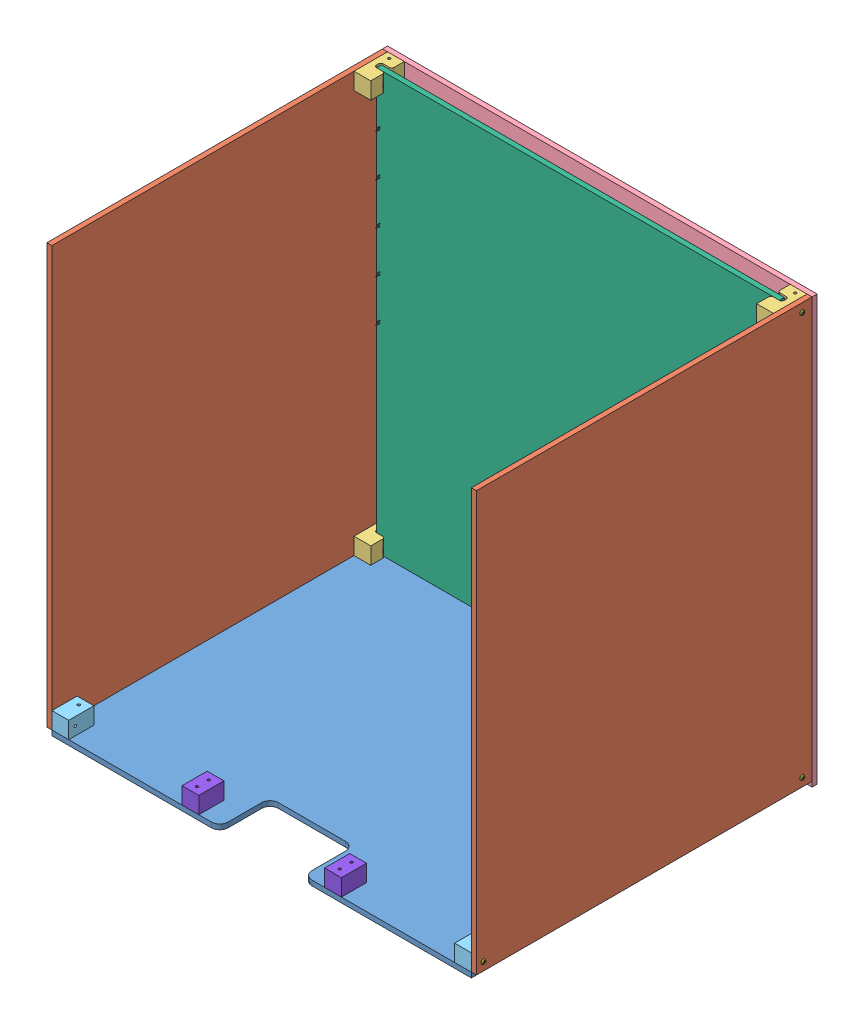
SolidWorks assembly robot_dock, configuration Default. Lengths in mm.
Overall size (515 507.5 407.6).
37 component instances, 9 part files, 84 mates.
Components (placement in the parent):
- back_board-1: back_board [Default] at (-3.0743 -458.0455 33.4938) size (500 6 400)
- side_board-3: side_board [Default] at (496.9257 47.9545 33.4938) x (0 -1 0) z (0 0 1) size (500 6 400)
- side_board-4: side_board [Default] at (-9.0743 47.9545 33.4938) x (0 -1 0) z (0 0 1) size (500 6 400)
- connector-1: connector [Default] at (-3.0743 27.9545 35.3943) size (20 20 40)
- connector-2: connector [Default] at (496.9257 -432.0455 35.3943) x (-1 0 0) z (0 0 1) size (20 20 40)
- connector-4: connector [Default] at (496.9257 47.9545 35.3943) x (-1 0 0) z (0 0 1) size (20 20 40)
- connector-6: connector [Default] at (-3.0743 -452.0455 35.3943) size (20 20 40)
- top_board-1: top_board [Default] at (-3.0743 47.9545 27.4938) x (1 0 0) z (0 -1 0) size (512 6 506)
- back_connector-1: back_connector [Default] at (-3.0743 -452.0455 433.4938) x (1 0 0) z (0 1 0) size (20 30 20)
- back_connector-2: back_connector [Default] at (476.9257 -452.0455 433.4938) x (1 0 0) z (0 1 0) size (20 30 20)
- middle_board-2: middle_board [Default] at (486.9257 -452.0455 56.4938) x (0 1 0) z (-1 0 0) size (500.05 6.1 480)
- Screw_Machine_M3x20-1: Screw_Machine_M3x20 [Default] at (488.9257 -458.0455 39.4938) x (-0.837169 0 -0.546944) z (-0.546944 0 0.837169) size (5.5 21.5 5.5)
- Screw_Machine_M3x20-2: Screw_Machine_M3x20 [Default] at (480.9257 37.9545 27.4938) x (1 0 0) z (0 1 0) size (5.5 21.5 5.5)
- Screw_Machine_M3x20-6: Screw_Machine_M3x20 [Default] at (4.9257 -458.0455 39.4938) x (-1 0 0) z (0 0 1) size (5.5 21.5 5.5)
- Screw_Machine_M3x20-8: Screw_Machine_M3x20 [Default] at (502.9257 -442.0455 425.4938) x (0 0.381849 -0.924225) z (0 -0.924225 -0.381849) size (5.5 21.5 5.5)
- Screw_Machine_M3x20-9: Screw_Machine_M3x20 [Default] at (6.9257 -458.0455 411.4938) x (-0.837169 0 -0.546944) z (-0.546944 0 0.837169) size (5.5 21.5 5.5)
- Screw_Machine_M3x20-10: Screw_Machine_M3x20 [Default] at (-9.0743 -442.0455 45.4938) x (0 1 0) z (0 0 1) size (5.5 21.5 5.5)
- Screw_Machine_M3x20-11: Screw_Machine_M3x20 [Default] at (-9.0743 -442.0455 425.4938) x (0 1 0) z (0 0 1) size (5.5 21.5 5.5)
- Screw_Machine_M3x20-12: Screw_Machine_M3x20 [Default] at (-9.0743 37.9545 45.4938) x (0 1 0) z (0 0 1) size (5.5 21.5 5.5)
- Screw_Machine_M3x20-13: Screw_Machine_M3x20 [Default] at (12.9257 -442.0455 27.4938) x (1 0 0) z (0 1 0) size (5.5 21.5 5.5)
- Screw_Machine_M3x20-14: Screw_Machine_M3x20 [Default] at (480.9257 -442.0455 27.4938) x (1 0 0) z (0 1 0) size (5.5 21.5 5.5)
- Screw_Machine_M3x20-16: Screw_Machine_M3x20 [Default] at (486.9257 -458.0455 411.4938) x (-0.837169 0 -0.546944) z (-0.546944 0 0.837169) size (5.5 21.5 5.5)
- Screw_Machine_M3x20-17: Screw_Machine_M3x20 [Default] at (502.9257 -442.0455 45.4938) x (0 0.381849 -0.924225) z (0 -0.924225 -0.381849) size (5.5 21.5 5.5)
- Screw_Machine_M3x20-19: Screw_Machine_M3x20 [Default] at (12.9257 37.9545 27.4938) x (1 0 0) z (0 1 0) size (5.5 21.5 5.5)
- Screw_Machine_M3x20-20: Screw_Machine_M3x20 [Default] at (502.9257 37.9545 45.4938) x (0 0.381849 -0.924225) z (0 -0.924225 -0.381849) size (5.5 21.5 5.5)
- robot_dock_pilot-1: robot_dock_pilot [Default] at (151.9257 -452.0455 433.4938) x (1 0 0) z (0 1 0) size (20 30 20)
- robot_dock_pilot-2: robot_dock_pilot [Default] at (321.9257 -452.0455 433.4938) x (1 0 0) z (0 1 0) size (20 30 20)
- Led Lamp 5 mm 3-1: Led Lamp 5 mm 3 [Default] at (482.9257 -12.0455 34.4938) x (0 0 -1) z (1 0 0) size (35.6 5.45 5.9)
- Led Lamp 5 mm 3-2: Led Lamp 5 mm 3 [Default] at (10.9257 -212.0455 34.4938) x (0 0 -1) z (1 0 0) size (35.6 5.45 5.9)
- Led Lamp 5 mm 3-3: Led Lamp 5 mm 3 [Default] at (10.9257 -62.0455 34.4938) x (0 0 -1) z (1 0 0) size (35.6 5.45 5.9)
- Led Lamp 5 mm 3-4: Led Lamp 5 mm 3 [Default] at (10.9257 -12.0455 34.4938) x (0 0 -1) z (1 0 0) size (35.6 5.45 5.9)
- Led Lamp 5 mm 3-5: Led Lamp 5 mm 3 [Default] at (482.9257 -212.0455 34.4938) x (0 0 -1) z (1 0 0) size (35.6 5.45 5.9)
- Led Lamp 5 mm 3-6: Led Lamp 5 mm 3 [Default] at (482.9257 -162.0455 34.4938) x (0 0 -1) z (1 0 0) size (35.6 5.45 5.9)
- Led Lamp 5 mm 3-7: Led Lamp 5 mm 3 [Default] at (10.9257 -162.0455 34.4938) x (0 0 -1) z (1 0 0) size (35.6 5.45 5.9)
- Led Lamp 5 mm 3-8: Led Lamp 5 mm 3 [Default] at (10.9257 -112.0455 34.4938) x (0 0 -1) z (1 0 0) size (35.6 5.45 5.9)
- Led Lamp 5 mm 3-10: Led Lamp 5 mm 3 [Default] at (482.9257 -112.0455 34.4938) x (0 0 -1) z (1 0 0) size (35.6 5.45 5.9)
- Led Lamp 5 mm 3-11: Led Lamp 5 mm 3 [Default] at (482.9257 -62.0455 34.4938) x (0 0 -1) z (0.182556 -0.983195 0) size (35.6 5.45 5.9)
Mates (geometry in assembly coordinates):
- Coincident2: coincident anti-aligned: plane of side_board-4 through (-3.0743 47.9545 33.4938) normal (1 0 0); plane of connector-1 through (-3.0743 47.9545 33.4938) normal (-1 0 0)
- Coincident3: coincident aligned: line of side_board-4 through (-3.0743 47.9545 33.4938) axis (0 0 1); line of connector-1 through (-3.0743 47.9545 33.4938) axis (0 0 1)
- Coincident4: coincident aligned: line of side_board-4 through (-3.0743 47.9545 33.4938) axis (0 -1 0); line of connector-1 through (-3.0743 47.9545 33.4938) axis (0 -1 0)
- Coincident5: coincident anti-aligned: plane of side_board-4 through (-3.0743 47.9545 33.4938) normal (1 0 0); plane of connector-6 through (-3.0743 -432.0455 33.4938) normal (-1 0 0)
- Coincident6: coincident aligned: line of side_board-4 through (-3.0743 -452.0455 33.4938) axis (0 0 1); line of connector-6 through (-3.0743 -452.0455 33.4938) axis (0 0 1)
- Coincident7: coincident aligned: line of side_board-4 through (-3.0743 47.9545 33.4938) axis (0 -1 0); line of connector-6 through (-3.0743 -432.0455 33.4938) axis (0 -1 0)
- Coincident8: coincident anti-aligned: plane of back_board-1 through (-3.0743 -452.0455 33.4938) normal (0 1 0); plane of connector-6 through (-3.0743 -452.0455 35.3943) normal (0 -1 0)
- Coincident9: coincident aligned: line of back_board-1 through (-3.0743 -452.0455 33.4938) axis (0 0 1); line of connector-6 through (-3.0743 -452.0455 33.4938) axis (0 0 1)
- Coincident10: coincident anti-aligned: line of back_board-1 through (-3.0743 -452.0455 33.4938) axis (1 0 0); line of connector-6 through (16.9257 -452.0455 33.4938) axis (-1 0 0)
- Coincident12: coincident anti-aligned: plane of back_board-1 through (-3.0743 -452.0455 33.4938) normal (0 1 0); plane of connector-2 through (496.9257 -452.0455 35.3943) normal (0 -1 0)
- Coincident13: coincident aligned: line of back_board-1 through (496.9257 -452.0455 33.4938) axis (0 0 1); line of connector-2 through (496.9257 -452.0455 33.4938) axis (0 0 1)
- Coincident14: coincident aligned: line of back_board-1 through (-3.0743 -452.0455 33.4938) axis (1 0 0); line of connector-2 through (476.9257 -452.0455 33.4938) axis (1 0 0)
- Coincident15: coincident anti-aligned: plane of side_board-3 through (496.9257 47.9545 33.4938) normal (-1 0 0); plane of connector-2 through (496.9257 -452.0455 33.4938) normal (1 0 0)
- Coincident16: coincident aligned: line of back_board-1 through (496.9257 -452.0455 33.4938) axis (0 0 1); line of side_board-3 through (496.9257 -452.0455 33.4938) axis (0 0 1)
- Coincident17: coincident anti-aligned: line of side_board-3 through (496.9257 47.9545 33.4938) axis (0 -1 0); line of connector-2 through (496.9257 -452.0455 33.4938) axis (0 1 0)
- Coincident18: coincident anti-aligned: plane of side_board-3 through (496.9257 47.9545 33.4938) normal (-1 0 0); plane of connector-4 through (496.9257 27.9545 33.4938) normal (1 0 0)
- Coincident19: coincident anti-aligned: line of side_board-3 through (496.9257 47.9545 33.4938) axis (0 -1 0); line of connector-4 through (496.9257 27.9545 33.4938) axis (0 1 0)
- Coincident20: coincident aligned: line of side_board-3 through (496.9257 47.9545 33.4938) axis (0 0 1); line of connector-4 through (496.9257 47.9545 33.4938) axis (0 0 1)
- Coincident21: coincident anti-aligned: plane of connector-4 through (496.9257 27.9545 33.4938) normal (0 0 -1); plane of top_board-1 through (-3.0743 47.9545 33.4938) normal (0 0 1)
- Coincident23: coincident aligned: line of connector-4 through (476.9257 47.9545 33.4938) axis (1 0 0); line of top_board-1 through (-9.0743 47.9545 33.4938) axis (1 0 0)
- Coincident24: coincident anti-aligned: plane of back_board-1 through (-3.0743 -452.0455 33.4938) normal (0 1 0); plane of back_connector-1 through (-3.0743 -452.0455 403.4938) normal (0 -1 0)
- Coincident25: coincident anti-aligned: line of side_board-4 through (-3.0743 47.9545 433.4938) axis (0 -1 0); line of back_connector-1 through (-3.0743 -452.0455 433.4938) axis (0 1 0)
- Coincident26: coincident anti-aligned: plane of side_board-3 through (496.9257 47.9545 33.4938) normal (-1 0 0); plane of back_connector-2 through (496.9257 -452.0455 403.4938) normal (1 0 0)
- Coincident27: coincident aligned: line of side_board-3 through (496.9257 47.9545 433.4938) axis (0 -1 0); line of back_connector-2 through (496.9257 -432.0455 433.4938) axis (0 -1 0)
- Coincident28: coincident anti-aligned: plane of back_board-1 through (-3.0743 -452.0455 33.4938) normal (0 1 0); plane of back_connector-2 through (476.9257 -452.0455 403.4938) normal (0 -1 0)
- Coincident30: coincident aligned: line of side_board-3 through (502.9257 47.9545 33.4938) axis (0 -1 0); line of top_board-1 through (502.9257 47.9545 33.4938) axis (0 -1 0)
- Coincident31: coincident anti-aligned: plane of back_board-1 through (-3.0743 -452.0455 33.4938) normal (0 1 0); plane of middle_board-2 through (486.9257 -452.0455 50.4938) normal (0 -1 0)
- Coincident32: coincident anti-aligned: plane of connector-1 through (3.9257 27.9545 56.4938) normal (0 0 -1); plane of middle_board-2 through (486.9257 -452.0455 56.4938) normal (0 0 1)
- Coincident33: coincident aligned: line of middle_board-2 through (6.9257 -452.0455 56.4938) axis (0 1 0); line of connector-1 through (6.9257 27.9545 56.4938) axis (0 1 0)
- Concentric1: concentric anti-aligned: cylinder of side_board-4 through (-3.0743 37.9545 45.4938) axis (-1 0 0) radius 1.525; cylinder of Screw_Machine_M3x20-12 through (10.9257 37.9545 45.4938) axis (1 0 0) radius 1.5
- Coincident34: coincident anti-aligned: plane of side_board-4 through (-9.0743 47.9545 33.4938) normal (-1 0 0); circle of Screw_Machine_M3x20-12
- Concentric2: concentric anti-aligned: cylinder of side_board-4 through (-3.0743 -442.0455 425.4938) axis (-1 0 0) radius 1.5; cylinder of Screw_Machine_M3x20-11 through (10.9257 -442.0455 425.4938) axis (1 0 0) radius 1.5
- Coincident37: coincident anti-aligned: plane of side_board-4 through (-9.0743 47.9545 33.4938) normal (-1 0 0); circle of Screw_Machine_M3x20-11
- Concentric3: concentric anti-aligned: cylinder of side_board-4 through (-3.0743 -442.0455 45.4938) axis (-1 0 0) radius 1.525; cylinder of Screw_Machine_M3x20-10 through (10.9257 -442.0455 45.4938) axis (1 0 0) radius 1.5
- Coincident38: coincident anti-aligned: plane of side_board-4 through (-9.0743 47.9545 33.4938) normal (-1 0 0); circle of Screw_Machine_M3x20-10
- Concentric4: concentric anti-aligned: cylinder of top_board-1 through (12.9257 37.9545 33.4938) axis (0 0 -1) radius 1.5; cylinder of Screw_Machine_M3x20-19 through (12.9257 37.9545 47.4938) axis (0 0 1) radius 1.5
- Coincident39: coincident anti-aligned: plane of top_board-1 through (-3.0743 47.9545 27.4938) normal (0 0 -1); circle of Screw_Machine_M3x20-19
- Concentric5: concentric anti-aligned: cylinder of top_board-1 through (12.9257 -442.0455 33.4938) axis (0 0 -1) radius 1.525; cylinder of Screw_Machine_M3x20-13 through (12.9257 -442.0455 47.4938) axis (0 0 1) radius 1.5
- Coincident40: coincident anti-aligned: plane of top_board-1 through (-3.0743 47.9545 27.4938) normal (0 0 -1); circle of Screw_Machine_M3x20-13
- Concentric6: concentric anti-aligned: cylinder of top_board-1 through (480.9257 -442.0455 33.4938) axis (0 0 -1) radius 1.5; cylinder of Screw_Machine_M3x20-14 through (480.9257 -442.0455 47.4938) axis (0 0 1) radius 1.5
- Coincident41: coincident anti-aligned: plane of top_board-1 through (-3.0743 47.9545 27.4938) normal (0 0 -1); circle of Screw_Machine_M3x20-14
- Concentric7: concentric anti-aligned: cylinder of top_board-1 through (480.9257 37.9545 33.4938) axis (0 0 -1) radius 1.5; cylinder of Screw_Machine_M3x20-2 through (480.9257 37.9545 47.4938) axis (0 0 1) radius 1.5
- Coincident42: coincident anti-aligned: plane of top_board-1 through (-3.0743 47.9545 27.4938) normal (0 0 -1); circle of Screw_Machine_M3x20-2
- Concentric8: concentric aligned: cylinder of side_board-3 through (502.9257 37.9545 45.4938) axis (-1 0 0) radius 1.525; cylinder of Screw_Machine_M3x20-20 through (482.9257 37.9545 45.4938) axis (-1 0 0) radius 1.5
- Coincident43: coincident anti-aligned: plane of side_board-3 through (502.9257 47.9545 33.4938) normal (1 0 0); circle of Screw_Machine_M3x20-20
- Concentric9: concentric aligned: cylinder of side_board-3 through (502.9257 -442.0455 45.4938) axis (-1 0 0) radius 1.525; cylinder of Screw_Machine_M3x20-17 through (482.9257 -442.0455 45.4938) axis (-1 0 0) radius 1.5
- Coincident44: coincident anti-aligned: plane of side_board-3 through (502.9257 47.9545 33.4938) normal (1 0 0); circle of Screw_Machine_M3x20-17
- Coincident45: coincident anti-aligned: cylinder of back_board-1 through (4.9257 -452.0455 39.4938) axis (0 -1 0) radius 1.5; circle of Screw_Machine_M3x20-6
- Coincident46: coincident anti-aligned: plane of back_board-1 through (-3.0743 -458.0455 33.4938) normal (0 -1 0); plane of Screw_Machine_M3x20-6 through (4.9257 -458.0455 42.0995) normal (0 1 0)
- Concentric10: concentric anti-aligned: cylinder of back_board-1 through (488.9257 -452.0455 39.4938) axis (0 -1 0) radius 1.525; cylinder of Screw_Machine_M3x20-1 through (488.9257 -438.0455 39.4938) axis (0 1 0) radius 1.5
- Coincident47: coincident anti-aligned: plane of back_board-1 through (-3.0743 -458.0455 33.4938) normal (0 -1 0); circle of Screw_Machine_M3x20-1
- Concentric11: concentric anti-aligned: cylinder of back_board-1 through (486.9257 -452.0455 411.4938) axis (0 -1 0) radius 1.5; cylinder of Screw_Machine_M3x20-16 through (486.9257 -438.0455 411.4938) axis (0 1 0) radius 1.5
- Coincident48: coincident anti-aligned: plane of back_board-1 through (-3.0743 -458.0455 33.4938) normal (0 -1 0); plane of Screw_Machine_M3x20-16 through (485.5006 -458.0455 413.6752) normal (0 1 0)
- Concentric12: concentric anti-aligned: cylinder of back_board-1 through (6.9257 -452.0455 411.4938) axis (0 -1 0) radius 1.5; cylinder of Screw_Machine_M3x20-9 through (6.9257 -438.0455 411.4938) axis (0 1 0) radius 1.5
- Coincident49: coincident anti-aligned: plane of back_board-1 through (-3.0743 -458.0455 33.4938) normal (0 -1 0); circle of Screw_Machine_M3x20-9
- Concentric13: concentric aligned: cylinder of side_board-3 through (502.9257 -442.0455 425.4938) axis (-1 0 0) radius 1.5; cylinder of Screw_Machine_M3x20-8 through (482.9257 -442.0455 425.4938) axis (-1 0 0) radius 1.5
- Coincident50: coincident anti-aligned: plane of side_board-3 through (502.9257 47.9545 33.4938) normal (1 0 0); circle of Screw_Machine_M3x20-8
- Concentric14: concentric aligned: cylinder of back_board-1 through (161.9257 -462.0455 425.4938) axis (0 1 0) radius 1.5; cylinder of robot_dock_pilot-1 through (161.9257 -432.0455 425.4938) axis (0 1 0) radius 1.5
- Concentric15: concentric aligned: cylinder of back_board-1 through (161.9257 -462.0455 411.4938) axis (0 1 0) radius 1.5; cylinder of robot_dock_pilot-1 through (161.9257 -432.0455 411.4938) axis (0 1 0) radius 1.5
- Coincident51: coincident anti-aligned: plane of back_board-1 through (-3.0743 -452.0455 33.4938) normal (0 1 0); plane of robot_dock_pilot-1 through (151.9257 -452.0455 403.4938) normal (0 -1 0)
- Concentric16: concentric aligned: cylinder of back_board-1 through (331.9257 -462.0455 425.4938) axis (0 1 0) radius 1.5; cylinder of robot_dock_pilot-2 through (331.9257 -432.0455 425.4938) axis (0 1 0) radius 1.5
- Concentric17: concentric aligned: cylinder of back_board-1 through (331.9257 -462.0455 411.4938) axis (0 1 0) radius 1.5; cylinder of robot_dock_pilot-2 through (331.9257 -432.0455 411.4938) axis (0 1 0) radius 1.5
- Coincident53: coincident anti-aligned: plane of back_board-1 through (-3.0743 -452.0455 33.4938) normal (0 1 0); plane of robot_dock_pilot-2 through (321.9257 -452.0455 403.4938) normal (0 -1 0)
- Concentric18: concentric anti-aligned: cylinder of top_board-1 through (482.9257 -12.0455 33.4938) axis (0 0 -1) radius 2.5; cylinder of Led Lamp 5 mm 3-1 through (482.9257 -12.0455 33.4938) axis (0 0 1) radius 2.5
- Coincident54: coincident anti-aligned: plane of top_board-1 through (-3.0743 47.9545 33.4938) normal (0 0 1); plane of Led Lamp 5 mm 3-1 through (482.9257 -12.0455 33.4938) normal (0 0 -1)
- Concentric20: concentric anti-aligned: cylinder of top_board-1 through (10.9257 -212.0455 33.4938) axis (0 0 -1) radius 2.5; cylinder of Led Lamp 5 mm 3-2 through (10.9257 -212.0455 33.4938) axis (0 0 1) radius 2.5
- Concentric21: concentric anti-aligned: cylinder of top_board-1 through (10.9257 -162.0455 33.4938) axis (0 0 -1) radius 2.5; cylinder of Led Lamp 5 mm 3-7 through (10.9257 -162.0455 33.4938) axis (0 0 1) radius 2.5
- Concentric22: concentric anti-aligned: cylinder of top_board-1 through (10.9257 -112.0455 33.4938) axis (0 0 -1) radius 2.5; cylinder of Led Lamp 5 mm 3-8 through (10.9257 -112.0455 33.4938) axis (0 0 1) radius 2.5
- Concentric23: concentric anti-aligned: cylinder of top_board-1 through (10.9257 -62.0455 33.4938) axis (0 0 -1) radius 2.5; cylinder of Led Lamp 5 mm 3-3 through (10.9257 -62.0455 33.4938) axis (0 0 1) radius 2.5
- Concentric24: concentric anti-aligned: cylinder of top_board-1 through (10.9257 -12.0455 33.4938) axis (0 0 -1) radius 2.5; cylinder of Led Lamp 5 mm 3-4 through (10.9257 -12.0455 33.4938) axis (0 0 1) radius 2.5
- Concentric25: concentric anti-aligned: cylinder of top_board-1 through (482.9257 -212.0455 33.4938) axis (0 0 -1) radius 2.5; cylinder of Led Lamp 5 mm 3-5 through (482.9257 -212.0455 33.4938) axis (0 0 1) radius 2.5
- Concentric26: concentric anti-aligned: cylinder of top_board-1 through (482.9257 -162.0455 33.4938) axis (0 0 -1) radius 2.5; cylinder of Led Lamp 5 mm 3-6 through (482.9257 -162.0455 33.4938) axis (0 0 1) radius 2.5
- Concentric27: concentric anti-aligned: cylinder of top_board-1 through (482.9257 -112.0455 33.4938) axis (0 0 -1) radius 2.5; cylinder of Led Lamp 5 mm 3-10 through (482.9257 -112.0455 33.4938) axis (0 0 1) radius 2.5
- Coincident56: coincident anti-aligned: plane of top_board-1 through (-3.0743 47.9545 33.4938) normal (0 0 1); plane of Led Lamp 5 mm 3-10 through (482.9257 -112.0455 33.4938) normal (0 0 -1)
- Coincident57: coincident anti-aligned: plane of top_board-1 through (-3.0743 47.9545 33.4938) normal (0 0 1); plane of Led Lamp 5 mm 3-6 through (482.9257 -162.0455 33.4938) normal (0 0 -1)
- Coincident58: coincident anti-aligned: plane of top_board-1 through (-3.0743 47.9545 33.4938) normal (0 0 1); plane of Led Lamp 5 mm 3-5 through (482.9257 -212.0455 33.4938) normal (0 0 -1)
- Coincident59: coincident anti-aligned: plane of top_board-1 through (-3.0743 47.9545 33.4938) normal (0 0 1); plane of Led Lamp 5 mm 3-3 through (10.9257 -62.0455 33.4938) normal (0 0 -1)
- Coincident60: coincident anti-aligned: plane of top_board-1 through (-3.0743 47.9545 33.4938) normal (0 0 1); plane of Led Lamp 5 mm 3-4 through (10.9257 -12.0455 33.4938) normal (0 0 -1)
- Coincident61: coincident anti-aligned: plane of top_board-1 through (-3.0743 47.9545 33.4938) normal (0 0 1); plane of Led Lamp 5 mm 3-3 through (10.9257 -62.0455 33.4938) normal (0 0 -1)
- Coincident62: coincident anti-aligned: plane of top_board-1 through (-3.0743 47.9545 33.4938) normal (0 0 1); plane of Led Lamp 5 mm 3-8 through (10.9257 -112.0455 33.4938) normal (0 0 -1)
- Coincident63: coincident anti-aligned: plane of top_board-1 through (-3.0743 47.9545 33.4938) normal (0 0 1); plane of Led Lamp 5 mm 3-7 through (10.9257 -162.0455 33.4938) normal (0 0 -1)
- Coincident64: coincident anti-aligned: plane of top_board-1 through (-3.0743 47.9545 33.4938) normal (0 0 1); plane of Led Lamp 5 mm 3-2 through (10.9257 -212.0455 33.4938) normal (0 0 -1)
- Concentric28: concentric: cylinder of top_board-1 through (482.9257 -62.0455 33.4938) axis (0 0 -1) radius 2.5; cylinder of Led Lamp 5 mm 3-11 through (482.9257 -62.0455 14.7613) axis (0 0 1) radius 2.5
- Coincident66: coincident anti-aligned: plane of top_board-1 through (-3.0743 47.9545 33.4938) normal (0 0 1); plane of Led Lamp 5 mm 3-11 through (482.9257 -62.0455 33.4938) normal (0 0 -1)
